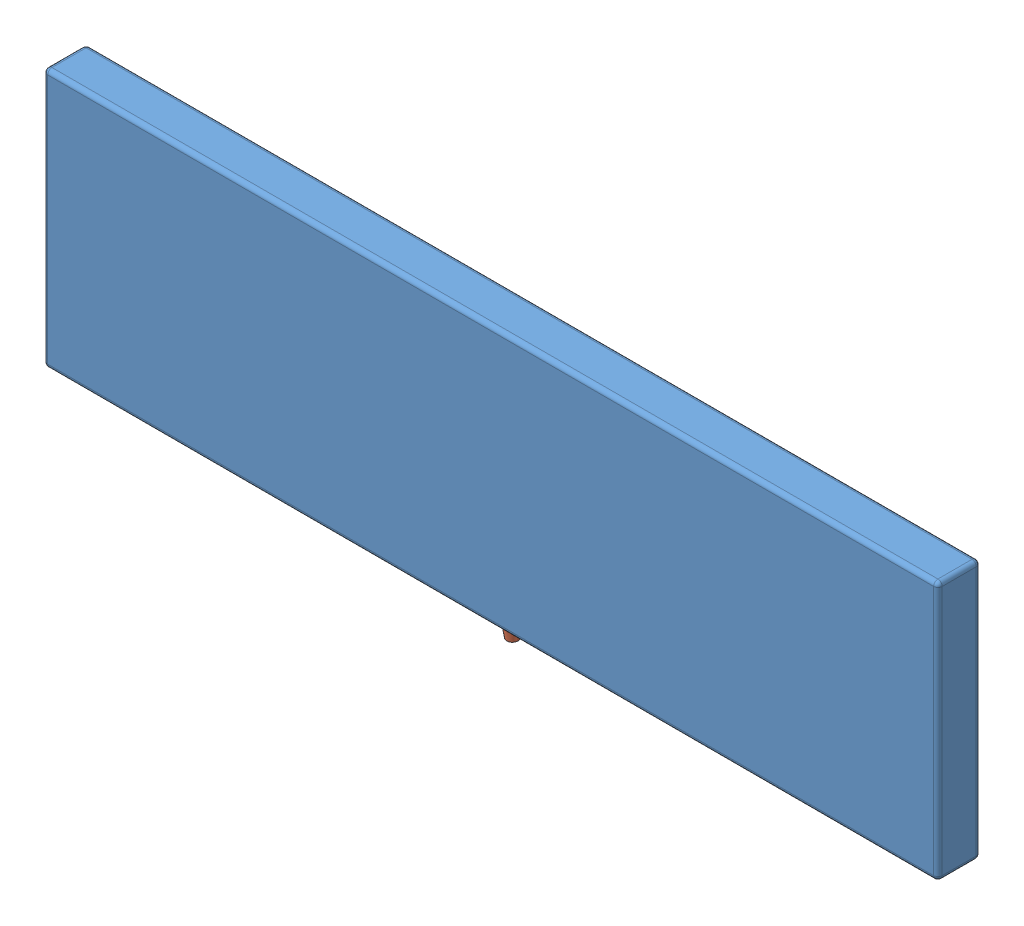
SolidWorks assembly Rueckwand, configuration Standard. Lengths in mm.
Overall size (2104.2 660.82 108.39).
2 component instances, 2 part files, 5 mates.
Components (placement in the parent):
- Rueckwand-1: Rueckwand [Standard] at (-1050 -220 920.2012) x (-1 0 0) z (0 1 0) size (2104.2 108.39 608.28)
- Standfuss-1: Standfuss [Standard] at (-1060.9826 -218.2982 927.5163) x (-1 0 0) z (0 0.999999 0.001172) size (43.37 42.87 53.74)
Mates (geometry in assembly coordinates):
- Deckungsgleich1: coincident anti-aligned: plane of Rueckwand-1 through (-2100 -608.1981 2330.2012) normal (0 -1 0); plane of Standfuss-1 through (-1023.7669 -608.1981 2348.0647) normal (0 1 0)
- Abstand1: distance = 40 mm: line of Standfuss-1 through (-1050 -660.0005 2379.1602) axis (0 0.999801 0.019937); line of Rueckwand-1 through (-2090 -608.1981 2420.2012) axis (1 0 0)
- Abstand2: distance = 1040 mm: line of Standfuss-1 through (-1050 -660.0005 2379.1602) axis (0 0.999801 0.019937); line of Rueckwand-1 through (-10 -608.1981 2340.2012) axis (0 0 1)
- Deckungsgleich4: coincident aligned: plane of Rueckwand-1 through (-2100 0 2330.2012) normal (0 1 0); plane of assembly through (0 0 0) normal (0 1 0)
- Deckungsgleich7: coincident aligned: plane of Rueckwand-1 through (0 0 2330.2012) normal (1 0 0); plane of assembly through (0 0 0) normal (1 0 0)
